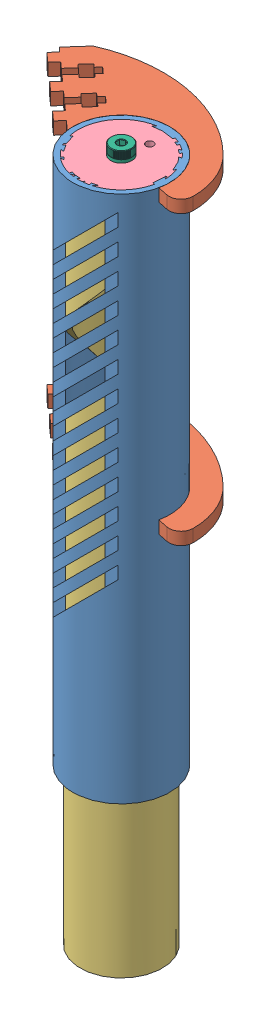
SolidWorks assembly Vacuum Tube, configuration Default. Lengths in mm.
Overall size (116.78 367.51 113.73).
9 component instances, 7 part files, 17 mates.
Components (placement in the parent):
- OUTSIDE TUBE, VACUUM TUBE-1: OUTSIDE TUBE, VACUUM TUBE [Default] at (166.0633 42.919 -65.2003) size (51.31 279.4 51.31)
- BRACKET, VACUUM TUBE-1: BRACKET, VACUUM TUBE [Default] at (137.2136 322.319 -58.2897) x (0.745357 0 0.666665) z (0 -1 0) size (100.99 62.26 6.6)
- BRACKET, VACUUM TUBE-2: BRACKET, VACUUM TUBE [Default] at (137.2136 170.173 -58.2897) x (0.745357 0 0.666665) z (0 -1 0) size (100.99 62.26 6.6)
- INSIDE TUBE, VACUUM TUBE-1: INSIDE TUBE, VACUUM TUBE [Default] at (166.0633 -39.631 -65.2003) x (-0.64833 0 -0.761359) z (0.761359 0 -0.64833) size (43.59 355.6 43.44)
- OUTSIDE TUBE CAP, VACUUM TUBE-1: OUTSIDE TUBE CAP, VACUUM TUBE [Default] at (166.0633 317.239 -65.2003) x (0.206589 0 -0.978428) z (0.978428 0 0.206589) size (45.72 5.08 45.72)
- INSIDE TUBE CAP, VACUUM TUBE-1: INSIDE TUBE CAP, VACUUM TUBE [Default] at (166.0633 310.889 -65.2003) size (37.08 5.08 37.08)
- 91259A574-1: 91259A574 [Default] at (166.0633 322.319 -65.2003) size (11.11 23.02 11.11)
- 95606A431-1: 95606A431 [Default] at (166.0633 317.239 -65.2003) x (1 0 0) z (0 1 0) size (12.7 12.7 0.51)
- 95606A431-2: 95606A431 [Default] at (166.0633 316.731 -65.2003) x (1 0 0) z (0 1 0) size (12.7 12.7 0.51)
Mates (geometry in assembly coordinates):
- Concentric1: concentric anti-aligned: cylinder of OUTSIDE TUBE, VACUUM TUBE-1 through (166.0633 322.319 -65.2003) axis (0 -1 0) radius 25.654; cylinder of BRACKET, VACUUM TUBE-1 through (166.0633 315.715 -65.2003) axis (0 1 0) radius 25.654
- Coincident1: coincident aligned: plane of OUTSIDE TUBE, VACUUM TUBE-1 through (166.0633 322.319 -65.2003) normal (0 1 0); plane of BRACKET, VACUUM TUBE-1 through (137.2136 322.319 -58.2897) normal (0 1 0)
- Concentric2: concentric anti-aligned: cylinder of OUTSIDE TUBE, VACUUM TUBE-1 through (166.0633 322.319 -65.2003) axis (0 -1 0) radius 25.654; cylinder of BRACKET, VACUUM TUBE-2 through (166.0633 163.569 -65.2003) axis (0 1 0) radius 25.654
- Distance1: distance = 158.75 mm anti-aligned: plane of BRACKET, VACUUM TUBE-1 through (137.2136 322.319 -58.2897) normal (0 1 0); plane of BRACKET, VACUUM TUBE-2 through (137.2136 163.569 -58.2897) normal (0 -1 0)
- Concentric4: concentric aligned: cylinder of OUTSIDE TUBE, VACUUM TUBE-1 through (166.0633 322.319 -65.2003) axis (0 -1 0) radius 21.717; cylinder of INSIDE TUBE, VACUUM TUBE-1 through (166.0633 315.969 -65.2003) axis (0 -1 0) radius 21.717
- Concentric5: concentric aligned: cylinder of OUTSIDE TUBE, VACUUM TUBE-1 through (166.0633 322.319 -65.2003) axis (0 -1 0) radius 21.717; cylinder of OUTSIDE TUBE CAP, VACUUM TUBE-1 through (166.0633 322.319 -65.2003) axis (0 -1 0) radius 22.86
- Coincident4: coincident aligned: plane of OUTSIDE TUBE, VACUUM TUBE-1 through (166.0633 322.319 -65.2003) normal (0 1 0); plane of OUTSIDE TUBE CAP, VACUUM TUBE-1 through (166.0633 322.319 -65.2003) normal (0 1 0)
- Coincident5: coincident anti-aligned: cylinder of INSIDE TUBE, VACUUM TUBE-1 through (166.0633 315.969 -65.2003) axis (0 -1 0) radius 18.542; circle of INSIDE TUBE CAP, VACUUM TUBE-1
- Coincident6: coincident anti-aligned: circle of OUTSIDE TUBE CAP, VACUUM TUBE-1; circle of 91259A574-1
- Coincident7: coincident anti-aligned: plane of OUTSIDE TUBE CAP, VACUUM TUBE-1 through (166.0633 317.239 -65.2003) normal (0 -1 0); plane of 95606A431-1 through (166.0633 317.239 -65.2003) normal (0 1 0)
- Concentric6: concentric anti-aligned: cylinder of 91259A574-1 through (166.0633 322.319 -65.2003) axis (0 -1 0) radius 3.9688; cylinder of 95606A431-1 through (166.0633 316.731 -65.2003) axis (0 1 0) radius 3.937
- Coincident8: coincident anti-aligned: plane of 95606A431-1 through (166.0633 316.731 -65.2003) normal (0 -1 0); plane of 95606A431-2 through (166.0633 316.731 -65.2003) normal (0 1 0)
- Concentric7: concentric anti-aligned: cylinder of 91259A574-1 through (166.0633 322.319 -65.2003) axis (0 -1 0) radius 3.9688; cylinder of 95606A431-2 through (166.0633 316.223 -65.2003) axis (0 1 0) radius 3.937
- Coincident9: coincident anti-aligned: plane of INSIDE TUBE, VACUUM TUBE-1 through (166.0633 315.969 -65.2003) normal (0 1 0); plane of 91259A574-1 through (166.0633 315.969 -65.2003) normal (0 -1 0)
- Distance2: distance = 16.7894 mm: line of OUTSIDE TUBE, VACUUM TUBE-1 through (148.8812 279.4828 -46.1503) axis (0 -1 0); plane of BRACKET, VACUUM TUBE-1
- Coincident10: coincident aligned: plane of BRACKET, VACUUM TUBE-1 through (127.9169 330.2947 -66.9456) normal (-0.666665 0 0.745357); plane of BRACKET, VACUUM TUBE-2 through (127.9169 178.1487 -66.9456) normal (-0.666665 0 0.745357)
- Coincident11: coincident aligned: plane of INSIDE TUBE, VACUUM TUBE-1 through (166.0633 315.969 -65.2003) normal (0 1 0); plane of INSIDE TUBE CAP, VACUUM TUBE-1 through (166.0633 315.969 -65.2003) normal (0 1 0)
